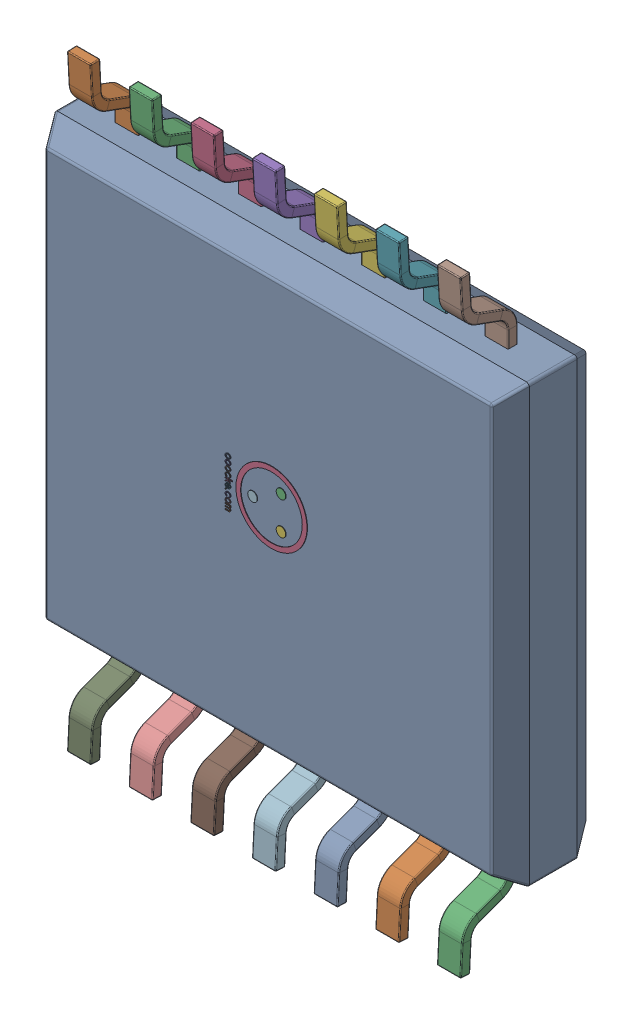
SolidWorks assembly U10, configuration Default. Lengths in mm.
Overall size (5 6.4 1.05).
17 component instances, 3 part files, 0 mates.
Components (placement in the parent):
- TSSOP14-1: TSSOP14 [Default] at (10.9 56 -0.4115) x (0 1 0) z (0 0 -1) size (6.4 5 1.05)
  - TSSOP14__X_CB_X_DC_X_CC_X_E5-1: TSSOP14__X_CB_X_DC_X_CC_X_E5 [Default] at origin size (4.6 5 1)
  - _X_D2_X_FD_X_BD_X_C5_0.9-1: _X_D2_X_FD_X_BD_X_C5_0.9 [Default] at (2.3 -1.95 0.53) x (0 1 0) z (0 0 1) size (0.25 0.9 0.6)
  - _X_D2_X_FD_X_BD_X_C5_0.9-2: _X_D2_X_FD_X_BD_X_C5_0.9 [Default] at (2.3 -1.3 0.53) x (0 1 0) z (0 0 1) size (0.25 0.9 0.6)
  - _X_D2_X_FD_X_BD_X_C5_0.9-3: _X_D2_X_FD_X_BD_X_C5_0.9 [Default] at (2.3 -0.65 0.53) x (0 1 0) z (0 0 1) size (0.25 0.9 0.6)
  - _X_D2_X_FD_X_BD_X_C5_0.9-4: _X_D2_X_FD_X_BD_X_C5_0.9 [Default] at (2.3 0 0.53) x (0 1 0) z (0 0 1) size (0.25 0.9 0.6)
  - _X_D2_X_FD_X_BD_X_C5_0.9-5: _X_D2_X_FD_X_BD_X_C5_0.9 [Default] at (2.3 0.65 0.53) x (0 1 0) z (0 0 1) size (0.25 0.9 0.6)
  - _X_D2_X_FD_X_BD_X_C5_0.9-6: _X_D2_X_FD_X_BD_X_C5_0.9 [Default] at (2.3 1.3 0.53) x (0 1 0) z (0 0 1) size (0.25 0.9 0.6)
  - _X_D2_X_FD_X_BD_X_C5_0.9-7: _X_D2_X_FD_X_BD_X_C5_0.9 [Default] at (2.3 1.95 0.53) x (0 1 0) z (0 0 1) size (0.25 0.9 0.6)
  - _X_D2_X_FD_X_BD_X_C5_0.9-8: _X_D2_X_FD_X_BD_X_C5_0.9 [Default] at (-2.3 -1.95 0.53) x (0 -1 0) z (0 0 1) size (0.25 0.9 0.6)
  - _X_D2_X_FD_X_BD_X_C5_0.9-9: _X_D2_X_FD_X_BD_X_C5_0.9 [Default] at (-2.3 -1.3 0.53) x (0 -1 0) z (0 0 1) size (0.25 0.9 0.6)
  - _X_D2_X_FD_X_BD_X_C5_0.9-10: _X_D2_X_FD_X_BD_X_C5_0.9 [Default] at (-2.3 -0.65 0.53) x (0 -1 0) z (0 0 1) size (0.25 0.9 0.6)
  - _X_D2_X_FD_X_BD_X_C5_0.9-11: _X_D2_X_FD_X_BD_X_C5_0.9 [Default] at (-2.3 0 0.53) x (0 -1 0) z (0 0 1) size (0.25 0.9 0.6)
  - _X_D2_X_FD_X_BD_X_C5_0.9-12: _X_D2_X_FD_X_BD_X_C5_0.9 [Default] at (-2.3 0.65 0.53) x (0 -1 0) z (0 0 1) size (0.25 0.9 0.6)
  - _X_D2_X_FD_X_BD_X_C5_0.9-13: _X_D2_X_FD_X_BD_X_C5_0.9 [Default] at (-2.3 1.3 0.53) x (0 -1 0) z (0 0 1) size (0.25 0.9 0.6)
  - _X_D2_X_FD_X_BD_X_C5_0.9-14: _X_D2_X_FD_X_BD_X_C5_0.9 [Default] at (-2.3 1.95 0.53) x (0 -1 0) z (0 0 1) size (0.25 0.9 0.6)
  - LOGOԲ0.25-1: LOGOԲ0.25 [Default] at (0.0665 0.0379 0.025) size (0.75 0.87 0.01)
